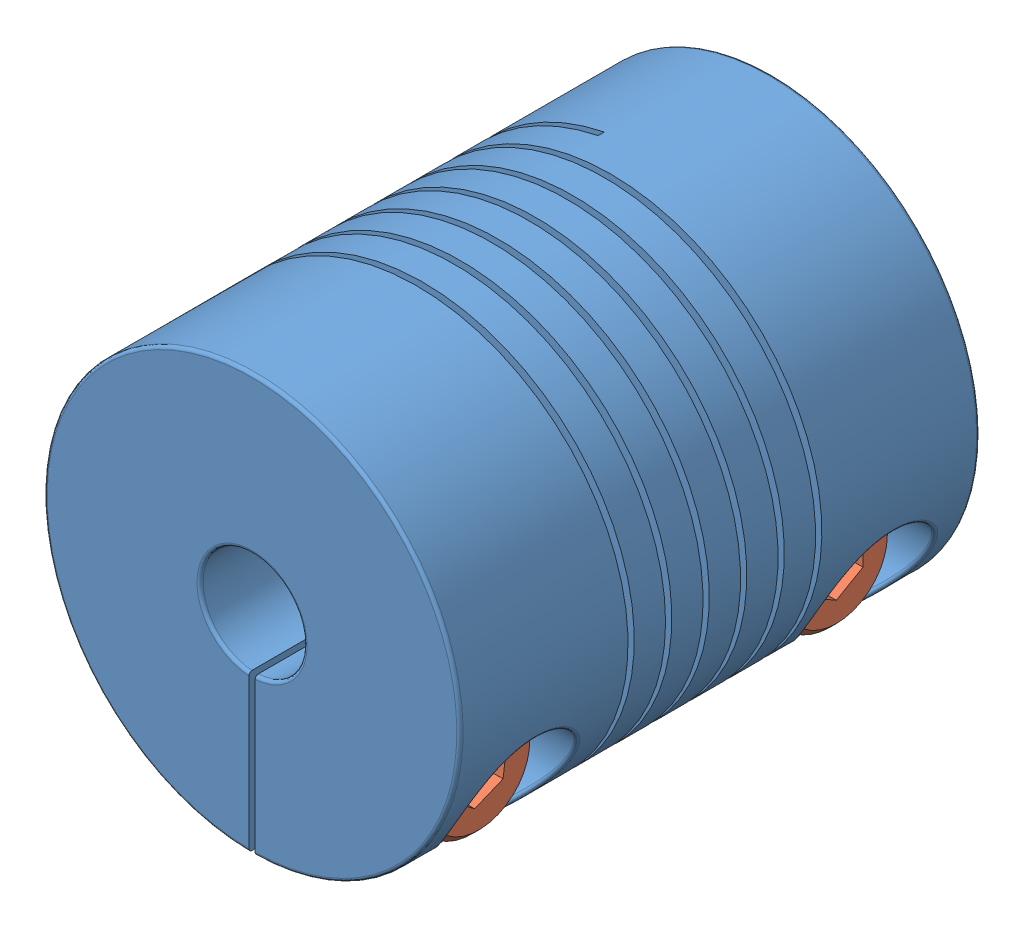
SolidWorks assembly 5mm x 8mm Flexible Coupling, configuration Default. Lengths in mm.
Overall size (20.7 20.83 25.02).
3 component instances, 2 part files, 4 mates.
Components (placement in the parent):
- 5mm x 8mm Flexible Coupling-1: 5mm x 8mm Flexible Coupling [Default] at (-34.9739 -2.4531 32.6221) size (20.7 20.83 25.02)
- Socket Head Cap Screw_AM-1: Socket Head Cap Screw_AM [B18.3.1M - 3 x 0.5 x 12 Hex SHCS -- 12NHX] at (-27.9739 -7.4531 28.7221) x (-1 0 0) z (0 -0.924225 -0.381849) size (15 5.5 5.5)
- Socket Head Cap Screw_AM-2: Socket Head Cap Screw_AM [B18.3.1M - 3 x 0.5 x 12 Hex SHCS -- 12NHX] at (-27.9739 -7.4531 11.5221) x (-1 0 0) z (0 0 -1) size (15 5.5 5.5)
Mates (geometry in assembly coordinates):
- Coincident1: coincident: plane of 5mm x 8mm Flexible Coupling-1 through (-30.9739 -7.4531 28.7221) normal (1 0 0); plane of Socket Head Cap Screw_AM-1 through (-30.9739 -6.403 26.1805) normal (-1 0 0)
- Coincident2: coincident aligned: circle of 5mm x 8mm Flexible Coupling-1; circle of Socket Head Cap Screw_AM-1
- Coincident3: coincident: plane of 5mm x 8mm Flexible Coupling-1 through (-30.9739 -7.4531 11.5221) normal (1 0 0); plane of Socket Head Cap Screw_AM-2 through (-30.9739 -4.7031 11.5221) normal (-1 0 0)
- Concentric1: concentric aligned: cylinder of 5mm x 8mm Flexible Coupling-1 through (-45.3254 -7.4531 11.5221) axis (1 0 0) radius 1.5; cylinder of Socket Head Cap Screw_AM-2 through (3.7761 -7.4531 11.5221) axis (1 0 0) radius 1.5
